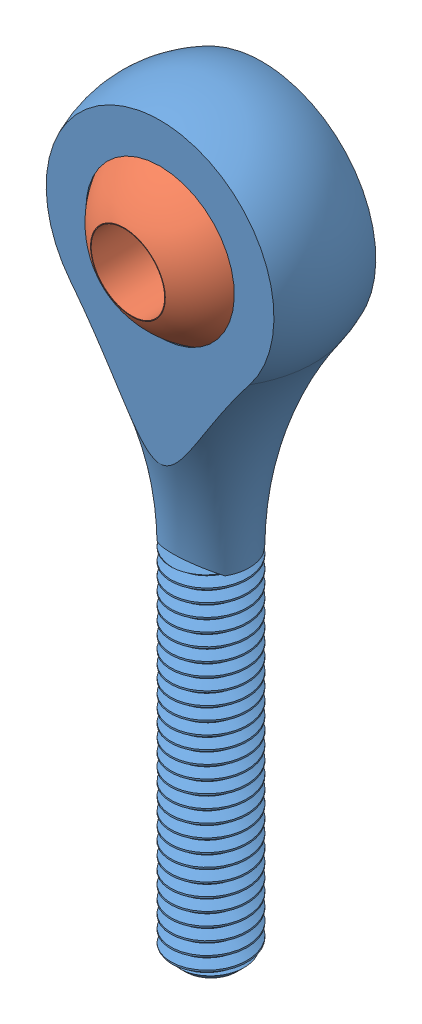
SolidWorks assembly McM - ball joint rod end - male RH M3x0.5 shank, 14mm L- 59935K110, configuration Default. Lengths in mm.
Overall size (10.05 30.34 8.39).
2 component instances, 2 part files, 1 mates.
Components (placement in the parent):
- McM - ball joint rod end - male RH M3x0.5 shank, 14mm L - rod end - 59935K110-1: McM - ball joint rod end - male RH M3x0.5 shank, 14mm L - rod end - 59935K110 [59935K11] at (-1.2413 -1.2876 1.5298) size (9.8 30 4)
- McM - ball joint rod end - male RH M3x0.5 shank, 14mm L - ball - 59935K110-1: McM - ball joint rod end - male RH M3x0.5 shank, 14mm L - ball - 59935K110 [59935K11] at (-1.2474 -1.2692 0.8939) x (0.999262 -0.002769 0.038318) z (-0.038414 -0.057744 0.997592) size (9.8 30 6.3)
Mates (geometry in assembly coordinates):
- Concentric1: concentric: sphere of McM - ball joint rod end - male RH M3x0.5 shank, 14mm L - ball - 59935K110-1; sphere of McM - ball joint rod end - male RH M3x0.5 shank, 14mm L - rod end - 59935K110-1
